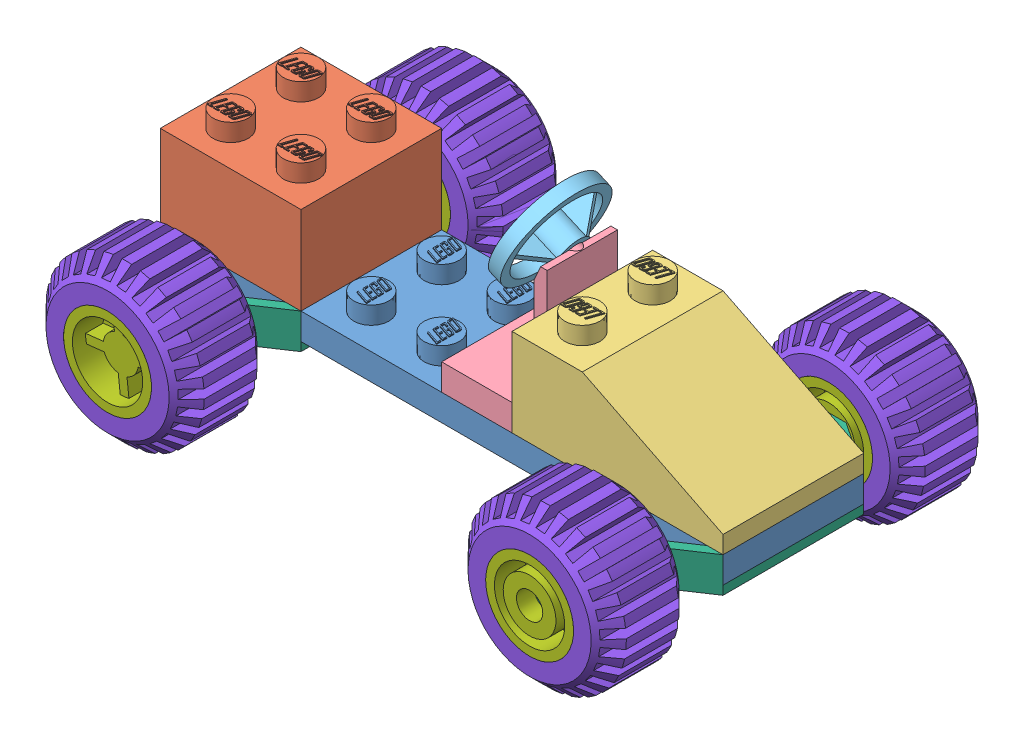
SolidWorks assembly toy car, configuration Default. Lengths in mm.
Overall size (75.35 37.36 44).
22 component instances, 8 part files, 19 mates.
Components (placement in the parent):
- Part3-1: Part3 [Default] at origin size (64 5.1 16)
- Part1-1: Part1 [Default] at (-24 3 0) size (16 12.1 16)
- Part2-1: Part2 [Default] at (8 3 8) x (0 0 -1) z (1 0 0) size (16 12.1 24)
- Part4-1: Part4 [Default] at (4 3 0) x (0 0 1) z (-1 0 0) size (16 15.65 8)
- Part5-1: Part5 [Default] at (6.875 16.1429 0) x (0.164328 0.375606 -0.912094) z (-0.916157 0.400819 0) size (11.8 11.8 3.5)
- Part8-1: Part8 [Default] at (-24 -1 0) x (0 0 1) z (-1 0 0) size (40 4 16)
- Part8-2: Part8 [Default] at (24 -1 0) x (0 0 -1) z (1 0 0) size (40 4 16)
- Assem1-1: Assem1 [Default] at (24 1 -17) x (-0.993897 0.11031 0) z (0 0 1) size (25.44 25.44 10)
  - Part6-1: Part6 [Default] at origin size (10 10 10)
  - Part7-2: Part7 [Default] at (0 0 -5) x (0.697936 -0.71616 0) z (0 0 1) size (18 17.99 10)
- Assem1-2: Assem1 [Default] at (24 1 17) x (-0.993897 0.11031 0) z (0 0 1) size (25.44 25.44 10)
  - Part6-1: Part6 [Default] at origin size (10 10 10)
  - Part7-2: Part7 [Default] at (0 0 -5) x (0.697936 -0.71616 0) z (0 0 1) size (18 17.99 10)
- Assem1-3: Assem1 [Default] at (-24 1 -17) x (0.993897 0.11031 0) z (0 0 -1) size (25.44 25.44 10)
  - Part6-1: Part6 [Default] at origin size (10 10 10)
  - Part7-2: Part7 [Default] at (0 0 -5) x (0.697936 -0.71616 0) z (0 0 1) size (18 17.99 10)
- Assem1-5: Assem1 [Default] at (-24 1 -17) x (0.993897 0.11031 0) z (0 0 -1) size (25.44 25.44 10)
  - Part6-1: Part6 [Default] at origin size (10 10 10)
  - Part7-2: Part7 [Default] at (0 0 -5) x (0.697936 -0.71616 0) z (0 0 1) size (18 17.99 10)
- Assem1-6: Assem1 [Default] at (-24 1 17) x (0.993897 0.11031 0) z (0 0 -1) size (25.44 25.44 10)
  - Part6-1: Part6 [Default] at origin size (10 10 10)
  - Part7-2: Part7 [Default] at (0 0 -5) x (0.697936 -0.71616 0) z (0 0 1) size (18 17.99 10)
Mates (geometry in assembly coordinates):
- Coincident1: coincident aligned: plane of Part3-1 through (32 3 8) normal (0 0 1); plane of Part1-1 through (-16 13 8) normal (0 0 1)
- Coincident3: coincident aligned: plane of Part3-1 through (-32 3 8) normal (-1 0 0); plane of Part1-1 through (-32 13 8) normal (-1 0 0)
- Coincident4: coincident anti-aligned: plane of Part3-1 through (0 3 0) normal (0 1 0); plane of Part1-1 through (-24 3 0) normal (0 -1 0)
- Coincident6: coincident aligned: plane of Part3-1 through (32 3 8) normal (0 0 1); plane of Part2-1 through (8 3 8) normal (0 0 1)
- Coincident7: coincident aligned: plane of Part3-1 through (32 3 8) normal (1 0 0); plane of Part2-1 through (32 5 -8) normal (1 0 0)
- Coincident8: coincident anti-aligned: plane of Part3-1 through (0 3 0) normal (0 1 0); plane of Part2-1 through (32 3 -8) normal (0 -1 0)
- Coincident9: coincident anti-aligned: plane of Part2-1 through (8 3 -8) normal (-1 0 0); plane of Part4-1 through (8 6 8) normal (1 0 0)
- Coincident10: coincident aligned: plane of Part3-1 through (32 3 8) normal (0 0 1); plane of Part4-1 through (0 6 8) normal (0 0 1)
- Coincident11: coincident anti-aligned: plane of Part3-1 through (0 3 0) normal (0 1 0); plane of Part4-1 through (4 3 0) normal (0 -1 0)
- Concentric1: concentric aligned: cylinder of Part4-1 through (3.6684 17.5457 0) axis (0.916157 -0.400819 0) radius 1.2; cylinder of Part5-1 through (3.6684 17.5457 0) axis (0.916157 -0.400819 0) radius 1.2
- Coincident12: coincident anti-aligned: plane of Part4-1 through (5.5 13 -8) normal (-0.916157 0.400819 0); plane of Part5-1 through (6.875 16.1429 0) normal (0.916157 -0.400819 0)
- Coincident13: coincident aligned: plane of Part3-1 through (32 3 8) normal (1 0 0); plane of Part8-2 through (32 0 8) normal (1 0 0)
- Coincident14: coincident anti-aligned: plane of Part2-1 through (8 3 -8) normal (0 0 -1); plane of Part8-2 through (30.1972 3 -8) normal (0 0 1)
- Coincident15: coincident anti-aligned: plane of Part3-1 through (0 0 0) normal (0 -1 0); plane of Part8-2 through (24 0 0) normal (0 1 0)
- Coincident16: coincident anti-aligned: plane of Part3-1 through (0 0 0) normal (0 -1 0); plane of Part8-1 through (-24 0 0) normal (0 1 0)
- Coincident17: coincident aligned: plane of Part3-1 through (-32 3 8) normal (-1 0 0); plane of Part8-1 through (-32 0 -8) normal (-1 0 0)
- Coincident18: coincident anti-aligned: plane of Part3-1 through (32 3 -8) normal (0 0 -1); plane of Part8-1 through (-30.1972 3 -8) normal (0 0 1)
- Concentric2: concentric aligned: cylinder of Part8-2 through (24 1 -20) axis (0 0 1) radius 1.5; cylinder of Assem1-1/Part6-1 through (24 1 -20) axis (0 0 1) radius 1.5
- Coincident19: coincident anti-aligned: plane of Part8-2 through (26 0 -12) normal (0 0 -1); plane of Assem1-1/Part6-1 through (24 1 -12) normal (0 0 1)
